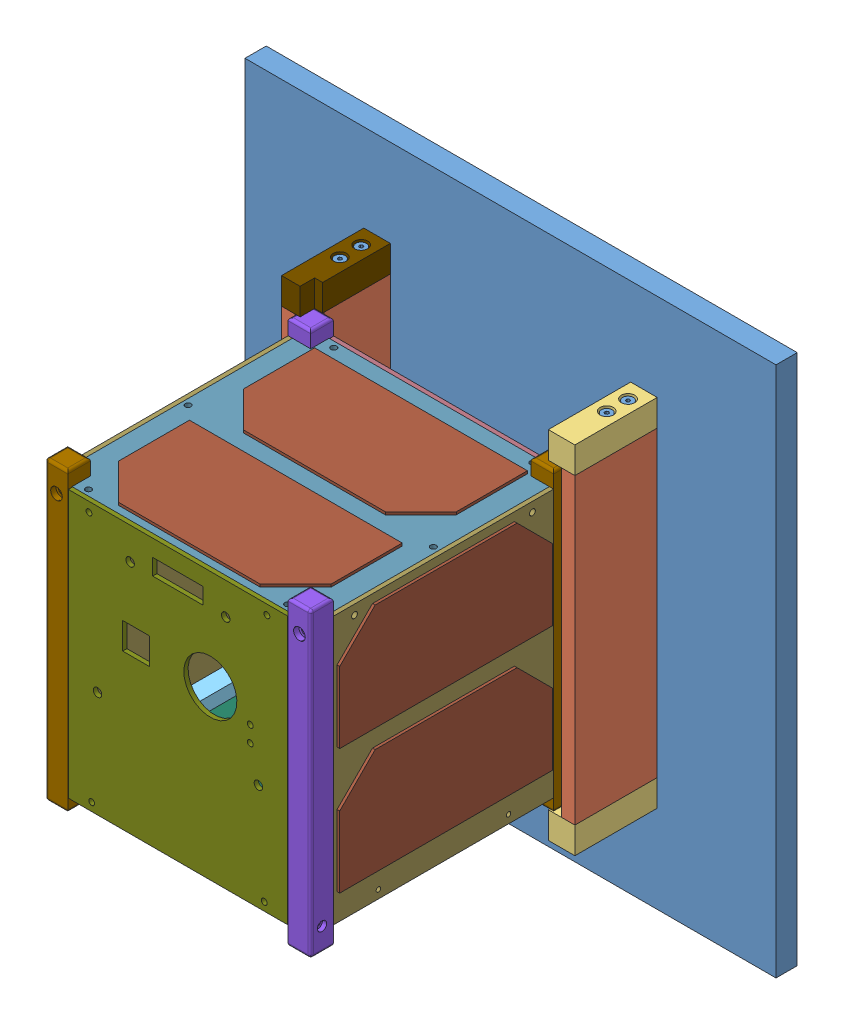
SolidWorks assembly stand_holizontal, configuration ﾃﾞﾌｫﾙﾄ. Lengths in mm.
Overall size (200 200 133).
67 component instances, 19 part files, 57 mates.
Components (placement in the parent):
- base_hori-1: base_hori [ﾃﾞﾌｫﾙﾄ] at (-92.1861 -100.1776 197.5) size (200 200 8)
- holi-1: holi [ﾃﾞﾌｫﾙﾄ] at (-47.4361 -57.1776 205.5) x (0 1 0) z (1 0 0) size (114 31 10)
- holi-3: holi [ﾃﾞﾌｫﾙﾄ] at (63.0639 56.8224 205.5) x (0 -1 0) z (-1 0 0) size (114 31 10)
- hori2-1: hori2 [ﾃﾞﾌｫﾙﾄ] at (63.0639 56.8224 205.5) x (-1 0 0) z (0 1 0) size (10 31 10)
- sample-1: sample [ﾃﾞﾌｫﾙﾄ] at (-42.4361 45.3224 330.5) x (0 0 -1) z (0 1 0) size (101 102 113.5)
  - B2_main-1: B2_main [ﾃﾞﾌｫﾙﾄ] at origin size (100 100 113.5)
    - B3_flame1-1: B3_flame1 [Default] at origin size (96.8 96.8 4)
    - B3_flame2-1: B3_flame2 [Default] at (76.5 -8.5 -87.5) x (-1 0 0) z (0 1 0) size (83 5 6.9)
    - B3_flame3-1: B3_flame3 [Default] at (100 -8.5 -85.4016) x (-1 0 0) z (0 1 0) size (6.9 5 83)
    - B3_flame4-1: B3_flame4 [Default] at (20.0069 -89.5 -26.6402) x (1 0 0) z (0 -1 0) size (6.9 16 10.5)
    - B3_flame5-1: B3_flame5 [Default] at (100 -8.5 11.5) x (-1 0 0) z (0 1 0) size (23.5 113.5 18.5)
    - B3_flame6-1: B3_flame6 [Default] at (91.5 -91.5 11.5) x (1 0 0) z (0 -1 0) size (23.5 111.5 18.5)
    - B3_flame5-2: B3_flame5 [Default] at (0 -91.5 11.5) x (1 0 0) z (0 -1 0) size (23.5 113.5 18.5)
    - B3_flame6-2: B3_flame6 [Default] at (8.5 -8.5 11.5) x (-1 0 0) z (0 1 0) size (23.5 111.5 18.5)
    - B3_flame2-2: B3_flame2 [Default] at (23.5 -91.5 -87.5) x (1 0 0) z (0 -1 0) size (83 5 6.9)
    - B3_flame3-2: B3_flame3 [Default] at (0 -91.5 -85.4016) x (1 0 0) z (0 -1 0) size (6.9 5 83)
    - B3_flame4-2: B3_flame4 [Default] at (79.9931 -10.5 -26.6402) x (-1 0 0) z (0 1 0) size (6.9 16 10.5)
    - B3_flame4-3: B3_flame4 [Default] at (-9.9069 -10.5 -26.6402) x (-1 0 0) z (0 1 0) size (6.9 16 10.5)
    - B3_flame4-4: B3_flame4 [Default] at (109.9069 -10.5 -61.3598) x (1 0 0) z (0 1 0) size (6.9 16 10.5)
    - B3_flame4-5: B3_flame4 [Default] at (109.9069 -89.5 -26.6402) x (1 0 0) z (0 -1 0) size (6.9 16 10.5)
    - B3_flame4-6: B3_flame4 [Default] at (-9.9069 -89.5 -61.3598) x (-1 0 0) z (0 -1 0) size (6.9 16 10.5)
    - B3_flame4-7: B3_flame4 [Default] at (79.9931 -89.5 -61.3598) x (-1 0 0) z (0 -1 0) size (6.9 16 10.5)
    - B3_flame4-8: B3_flame4 [Default] at (20.0069 -10.5 -61.3598) x (1 0 0) z (0 1 0) size (6.9 16 10.5)
    - B3_flame7-1: B3_flame7 [Default] at (4.25 -91.5 -96.25) x (1 0 0) z (0 -1 0) size (5.5 8.5 5)
    - B3_flame7-2: B3_flame7 [Default] at (95.75 -8.5 -96.25) x (-1 0 0) z (0 1 0) size (5.5 8.5 5)
  - B3_±Y_panel-1: B3_±Y_panel [Default] at (-6.4374 35.5175 36.7952) x (-1 0 0) z (0 0 -1) size (83 2.6 100.7)
    - Solar panel-1: Solar panel [Default] at (-43.4703 -35.5175 64.7205) size (80.15 1 40.15)
    - Solar panel-2: Solar panel [Default] at (-69.4046 -34.5175 111.8705) x (-1 0 0) z (0 0 1) size (80.15 1 40.15)
    - B2_±X_panel-2: B2_±X_panel [Default] at (-32.6974 -37.1175 99.3327) x (-1 0 0) z (0 0 -1) size (83 1.6 100.7)
  - B3_±Y_panel-2: B3_±Y_panel [Default] at (106.4374 -135.5175 36.7952) x (1 0 0) z (0 0 -1) size (83 2.6 100.7)
    - Solar panel-1: Solar panel [Default] at (-43.4703 -35.5175 64.7205) size (80.15 1 40.15)
    - Solar panel-2: Solar panel [Default] at (-69.4046 -34.5175 111.8705) x (-1 0 0) z (0 0 1) size (80.15 1 40.15)
    - B2_±X_panel-2: B2_±X_panel [Default] at (-32.6974 -37.1175 99.3327) x (-1 0 0) z (0 0 -1) size (83 1.6 100.7)
  - B3_+X_panel-1: B3_+X_panel [Default] at (78.7507 -74.7061 -48) x (0 1 0) z (0 0 -1) size (82.6 2.6 100.7)
    - Solar panel-2: Solar panel [Default] at (37.4682 21.2493 -21.6831) size (80.15 1 40.15)
    - Solar panel-3: Solar panel [Default] at (11.5339 21.2493 15.1831) x (-1 0 0) z (0 0 -1) size (80.15 1 40.15)
    - B3_+X_panel-1: B3_+X_panel [Default] at (0.9661 19.6493 -22.1375) size (82.6 1.6 100.7)
  - B3_+Z_panel-1: B3_+Z_panel [Default] at (-143.4944 -153.976 4.9) x (-1 0 0) z (0 1 0) size (96.8 2.6 96.8)
    - B2_+Z_panel-1: B2_+Z_panel [Default] at (-207.8501 -0.9 90.2045) size (96.8 1.6 96.8)
    - Solar panel-1: Solar panel [Default] at (-225.2113 0.7 116.9431) x (0 0 1) z (-1 0 0) size (80.15 1 40.15)
    - Solar panel-2: Solar panel [Default] at (-178.0613 1.7 91.0089) x (0 0 -1) z (-1 0 0) size (80.15 1 40.15)
  - B3_-Z_panel-1: B3_-Z_panel [ﾃﾞﾌｫﾙﾄ] at (67.2 -63 -89) x (1 0 0) z (0 -1 0) size (96.8 2.6 96.8)
    - B2_-Z_panel-1: B2_-Z_panel [Default] at (-49.4929 -4.5 -25.7556) x (0 0 1) z (1 0 0) size (96.8 1.6 96.8)
    - Solar panel-1: Solar panel [Default] at (15.6169 -6.1 -0.1079) x (0 0 1) z (1 0 0) size (80.15 1 40.15)
    - Solar panel-2: Solar panel [Default] at (-31.5331 -7.1 -26.0421) x (0 0 -1) z (1 0 0) size (80.15 1 40.15)
  - B3_-X_panel-1: B3_-X_panel [Default] at (0 -73.74 -25.8625) x (0 1 0) z (0 0 -1) size (82.6 1.6 100.7)
- hori2-3: hori2 [ﾃﾞﾌｫﾙﾄ] at (53.0639 -57.1776 205.5) x (1 0 0) z (0 -1 0) size (10 31 10)
- horiDS-1: horiDS [ﾃﾞﾌｫﾙﾄ] at (-47.4361 -57.1776 205.5) x (1 0 0) z (0 -1 0) size (10 31 10)
- horiDS2-1: horiDS2 [ﾃﾞﾌｫﾙﾄ] at (-37.4361 56.8224 205.5) x (-1 0 0) z (0 1 0) size (10 31 10)
- SSHS-M2-10-1: SSHS-M2-10 [ﾃﾞﾌｫﾙﾄ] at (58.0639 21.8193 201.5) x (0 0 1) z (-0.997527 0.070285 0) size (11.1 4 4)
- SSHS-M2-10-2: SSHS-M2-10 [ﾃﾞﾌｫﾙﾄ] at (58.0639 44.8224 201.5) x (0 0 1) z (-0.997527 0.070285 0) size (11.1 4 4)
- SSHS-M2-10-3: SSHS-M2-10 [ﾃﾞﾌｫﾙﾄ] at (58.3139 -0.1776 201.5) x (0 0 1) z (-0.997527 0.070285 0) size (11.1 4 4)
- SSHS-M2-10-4: SSHS-M2-10 [ﾃﾞﾌｫﾙﾄ] at (58.0639 -22.1651 201.5) x (0 0 1) z (-0.963225 0.268695 0) size (11.1 4 4)
- SSHS-M2-10-5: SSHS-M2-10 [ﾃﾞﾌｫﾙﾄ] at (58.0639 -45.1681 201.5) x (0 0 1) z (0.306571 -0.951848 0) size (11.1 4 4)
- SSHS-M2-10-6: SSHS-M2-10 [ﾃﾞﾌｫﾙﾄ] at (-42.1861 -0.1776 201.5) x (0 0 1) z (-0.997527 0.070285 0) size (11.1 4 4)
- SSHS-M2-10-7: SSHS-M2-10 [ﾃﾞﾌｫﾙﾄ] at (-42.4361 -22.1651 201.5) x (0 0 1) z (-0.997527 0.070285 0) size (11.1 4 4)
- SSHS-M2-10-8: SSHS-M2-10 [ﾃﾞﾌｫﾙﾄ] at (-42.4361 -45.1681 201.5) x (0 0 1) z (-0.997527 0.070285 0) size (11.1 4 4)
- SSHS-M2-10-9: SSHS-M2-10 [ﾃﾞﾌｫﾙﾄ] at (-42.4361 21.8193 201.5) x (0 0 1) z (-0.997527 0.070285 0) size (11.1 4 4)
- SSHS-M2-10-10: SSHS-M2-10 [ﾃﾞﾌｫﾙﾄ] at (-42.4361 44.8224 201.5) x (0 0 1) z (-0.997527 0.070285 0) size (11.1 4 4)
- SSHS-M2-10-11: SSHS-M2-10 [ﾃﾞﾌｫﾙﾄ] at (58.0639 65.2224 219.5) x (0 -1 0) z (0.48442 0 0.874835) size (11.1 4 4)
- SSHS-M2-10-12: SSHS-M2-10 [ﾃﾞﾌｫﾙﾄ] at (58.0639 65.2224 211.5) x (0 -1 0) z (0.528772 0 0.848764) size (11.1 4 4)
- SSHS-M2-10-13: SSHS-M2-10 [ﾃﾞﾌｫﾙﾄ] at (-42.4361 65.2224 219.5) x (0 -1 0) z (0.560755 0 0.827982) size (11.1 4 4)
- SSHS-M2-10-14: SSHS-M2-10 [ﾃﾞﾌｫﾙﾄ] at (-42.4361 65.2224 211.5) x (0 -1 0) z (0.50727 0 0.861787) size (11.1 4 4)
- SSHS-M2-10-15: SSHS-M2-10 [ﾃﾞﾌｫﾙﾄ] at (58.0639 -65.5776 219.5) x (0 1 0) z (0.536886 0 0.843655) size (11.1 4 4)
- SSHS-M2-10-16: SSHS-M2-10 [ﾃﾞﾌｫﾙﾄ] at (58.0639 -65.5776 211.5) x (0 1 0) z (0.577507 0 0.816386) size (11.1 4 4)
- SSHS-M2-10-17: SSHS-M2-10 [ﾃﾞﾌｫﾙﾄ] at (-42.4361 -65.5776 219.5) x (0 1 0) z (-0.546944 0 0.837169) size (11.1 4 4)
- SSHS-M2-10-18: SSHS-M2-10 [ﾃﾞﾌｫﾙﾄ] at (-42.4361 -65.5776 211.5) x (0 1 0) z (0.580214 0 0.814464) size (11.1 4 4)
Mates (geometry in assembly coordinates):
- Coincident2: coincident anti-aligned: plane of base_hori-1 through (-92.1861 -100.1776 205.5) normal (0 0 1); plane of holi-1 through (-37.4361 -57.1776 205.5) normal (0 0 -1)
- Coincident3: coincident anti-aligned: plane of base_hori-1 through (-92.1861 -100.1776 205.5) normal (0 0 1); plane of holi-3 through (53.0639 56.8224 205.5) normal (0 0 -1)
- Coincident6: coincident aligned: plane of holi-1 through (-37.4361 56.8224 205.5) normal (0 1 0); plane of holi-3 through (53.0639 56.8224 205.5) normal (0 1 0)
- Distance1: distance = 43 mm aligned: plane of holi-3 through (53.0639 56.8224 205.5) normal (0 1 0); plane of base_hori-1 through (-92.1861 99.8224 205.5) normal (0 1 0)
- Coincident15: coincident anti-aligned: plane of holi-1 through (-42.4361 -57.1776 205.5) normal (1 0 0); plane of sample-1/B2_main-1/B3_flame5-1 through (-42.4361 56.8224 230.5) normal (-1 0 0)
- Coincident16: coincident anti-aligned: plane of holi-3 through (58.0639 -57.1776 230.5) normal (0 0 1); plane of sample-1/B2_main-1/B3_flame6-1 through (57.5639 56.8224 230.5) normal (0 0 -1)
- Distance2: distance = 145.25 mm aligned: plane of base_hori-1 through (107.8139 -100.1776 205.5) normal (1 0 0); plane of holi-1 through (-37.4361 -57.1776 205.5) normal (1 0 0)
- Distance3: distance = 145.25 mm aligned: plane of holi-3 through (53.0639 56.8224 205.5) normal (-1 0 0); plane of base_hori-1 through (-92.1861 -100.1776 205.5) normal (-1 0 0)
- Coincident19: coincident anti-aligned: plane of holi-3 through (53.0639 -57.1776 205.5) normal (0 -1 0); plane of hori2-3 through (53.0639 -57.1776 205.5) normal (0 1 0)
- Coincident20: coincident aligned: plane of holi-3 through (63.0639 56.8224 205.5) normal (1 0 0); plane of hori2-3 through (63.0639 -67.1776 205.5) normal (1 0 0)
- Coincident21: coincident aligned: plane of holi-3 through (53.0639 56.8224 236.5) normal (0 0 1); plane of hori2-3 through (53.0639 -67.1776 236.5) normal (0 0 1)
- Coincident22: coincident anti-aligned: plane of holi-1 through (-37.4361 -57.1776 205.5) normal (0 -1 0); plane of horiDS-1 through (-47.4361 -57.1776 205.5) normal (0 1 0)
- Coincident23: coincident aligned: plane of holi-1 through (-47.4361 -57.1776 205.5) normal (-1 0 0); plane of horiDS-1 through (-47.4361 -67.1776 205.5) normal (-1 0 0)
- Coincident24: coincident aligned: plane of holi-1 through (-37.4361 -57.1776 236.5) normal (0 0 1); plane of horiDS-1 through (-47.4361 -67.1776 236.5) normal (0 0 1)
- Coincident28: coincident anti-aligned: plane of holi-3 through (53.0639 56.8224 205.5) normal (0 1 0); plane of hori2-1 through (63.0639 56.8224 205.5) normal (0 -1 0)
- Coincident29: coincident aligned: plane of holi-3 through (53.0639 56.8224 236.5) normal (0 0 1); plane of hori2-1 through (63.0639 66.8224 236.5) normal (0 0 1)
- Coincident30: coincident aligned: plane of holi-3 through (63.0639 56.8224 205.5) normal (1 0 0); plane of hori2-1 through (63.0639 66.8224 205.5) normal (1 0 0)
- Coincident34: coincident anti-aligned: plane of holi-1 through (-37.4361 56.8224 205.5) normal (0 1 0); plane of horiDS2-1 through (-37.4361 56.8224 205.5) normal (0 -1 0)
- Coincident35: coincident aligned: plane of holi-1 through (-47.4361 -57.1776 205.5) normal (-1 0 0); plane of horiDS2-1 through (-47.4361 66.8224 205.5) normal (-1 0 0)
- Coincident36: coincident aligned: plane of holi-1 through (-37.4361 -57.1776 236.5) normal (0 0 1); plane of horiDS2-1 through (-37.4361 66.8224 236.5) normal (0 0 1)
- Concentric1: concentric aligned: cylinder of horiDS-1 through (-42.4361 -67.1776 219.5) axis (0 -1 0) radius 2.5; cylinder of SSHS-M2-10-17 through (-42.4361 -55.5776 219.5) axis (0 -1 0) radius 0.8
- Coincident37: coincident aligned: plane of horiDS-1 through (-41.2361 -65.5776 219.5) normal (0 -1 0); circle of SSHS-M2-10-17
- Concentric2: concentric aligned: cylinder of horiDS-1 through (-42.4361 -67.1776 211.5) axis (0 -1 0) radius 2.5; cylinder of SSHS-M2-10-18 through (-42.4361 -55.5776 211.5) axis (0 -1 0) radius 0.8
- Coincident38: coincident aligned: plane of horiDS-1 through (-41.2361 -65.5776 211.5) normal (0 -1 0); circle of SSHS-M2-10-18
- Concentric3: concentric aligned: cylinder of hori2-3 through (58.0639 -67.1776 219.5) axis (0 -1 0) radius 2.5; cylinder of SSHS-M2-10-15 through (58.0639 -55.5776 219.5) axis (0 -1 0) radius 0.8
- Coincident39: coincident aligned: plane of hori2-3 through (59.2639 -65.5776 219.5) normal (0 -1 0); circle of SSHS-M2-10-15
- Concentric4: concentric aligned: cylinder of hori2-3 through (58.0639 -67.1776 211.5) axis (0 -1 0) radius 2.5; cylinder of SSHS-M2-10-16 through (58.0639 -55.5776 211.5) axis (0 -1 0) radius 0.8
- Coincident40: coincident aligned: plane of hori2-3 through (59.2639 -65.5776 211.5) normal (0 -1 0); circle of SSHS-M2-10-16
- Concentric5: concentric aligned: cylinder of hori2-1 through (58.0639 66.8224 219.5) axis (0 1 0) radius 1.2; cylinder of SSHS-M2-10-11 through (58.0639 55.2224 219.5) axis (0 1 0) radius 0.8
- Coincident41: coincident aligned: plane of hori2-1 through (56.8639 65.2224 219.5) normal (0 1 0); circle of SSHS-M2-10-11
- Concentric6: concentric aligned: cylinder of hori2-1 through (58.0639 66.8224 211.5) axis (0 1 0) radius 1.2; cylinder of SSHS-M2-10-12 through (58.0639 55.2224 211.5) axis (0 1 0) radius 0.8
- Coincident42: coincident aligned: plane of hori2-1 through (56.8639 65.2224 211.5) normal (0 1 0); circle of SSHS-M2-10-12
- Concentric7: concentric aligned: cylinder of horiDS2-1 through (-42.4361 66.8224 219.5) axis (0 1 0) radius 1.2; cylinder of SSHS-M2-10-13 through (-42.4361 55.2224 219.5) axis (0 1 0) radius 0.8
- Coincident43: coincident aligned: plane of horiDS2-1 through (-43.6361 65.2224 219.5) normal (0 1 0); circle of SSHS-M2-10-13
- Concentric8: concentric aligned: cylinder of horiDS2-1 through (-42.4361 66.8224 211.5) axis (0 1 0) radius 1.2; cylinder of SSHS-M2-10-14 through (-42.4361 55.2224 211.5) axis (0 1 0) radius 0.8
- Coincident44: coincident aligned: plane of horiDS2-1 through (-43.6361 65.2224 211.5) normal (0 1 0); circle of SSHS-M2-10-14
- Coincident45: coincident aligned: plane of SSHS-M2-10-9 through (-42.2956 23.8144 201.5) normal (0 0 1); plane of SSHS-M2-10-10 through (-42.2956 46.8175 201.5) normal (0 0 1)
- Coincident46: coincident aligned: plane of SSHS-M2-10-8 through (-42.2956 -43.173 201.5) normal (0 0 1); plane of SSHS-M2-10-9 through (-42.2956 23.8144 201.5) normal (0 0 1)
- Coincident47: coincident aligned: plane of SSHS-M2-10-7 through (-42.2956 -20.17 201.5) normal (0 0 1); plane of SSHS-M2-10-8 through (-42.2956 -43.173 201.5) normal (0 0 1)
- Coincident48: coincident aligned: plane of SSHS-M2-10-6 through (-42.0456 1.8175 201.5) normal (0 0 1); plane of SSHS-M2-10-7 through (-42.2956 -20.17 201.5) normal (0 0 1)
- Coincident49: coincident aligned: plane of SSHS-M2-10-5 through (56.1602 -45.7812 201.5) normal (0 0 1); plane of SSHS-M2-10-6 through (-42.0456 1.8175 201.5) normal (0 0 1)
- Coincident50: coincident aligned: plane of SSHS-M2-10-4 through (58.6013 -20.2386 201.5) normal (0 0 1); plane of SSHS-M2-10-5 through (56.1602 -45.7812 201.5) normal (0 0 1)
- Coincident51: coincident aligned: plane of SSHS-M2-10-3 through (58.4544 1.8175 201.5) normal (0 0 1); plane of SSHS-M2-10-4 through (58.6013 -20.2386 201.5) normal (0 0 1)
- Coincident52: coincident aligned: plane of SSHS-M2-10-2 through (58.2044 46.8175 201.5) normal (0 0 1); plane of SSHS-M2-10-3 through (58.4544 1.8175 201.5) normal (0 0 1)
- Coincident53: coincident aligned: plane of SSHS-M2-10-1 through (58.2044 23.8144 201.5) normal (0 0 1); plane of SSHS-M2-10-2 through (58.2044 46.8175 201.5) normal (0 0 1)
- Concentric9: concentric aligned: circle of base_hori-1; cylinder of SSHS-M2-10-2 through (58.0639 44.8224 211.5) axis (0 0 -1) radius 0.8
- Concentric10: concentric aligned: circle of base_hori-1; cylinder of SSHS-M2-10-1 through (58.0639 21.8193 211.5) axis (0 0 -1) radius 0.8
- Concentric11: concentric aligned: circle of base_hori-1; cylinder of SSHS-M2-10-3 through (58.3139 -0.1776 211.5) axis (0 0 -1) radius 0.8
- Concentric12: concentric aligned: circle of base_hori-1; cylinder of SSHS-M2-10-4 through (58.0639 -22.1651 211.5) axis (0 0 -1) radius 0.8
- Concentric13: concentric aligned: circle of base_hori-1; cylinder of SSHS-M2-10-5 through (58.0639 -45.1681 211.5) axis (0 0 -1) radius 0.8
- Concentric14: concentric aligned: circle of base_hori-1; cylinder of SSHS-M2-10-10 through (-42.4361 44.8224 211.5) axis (0 0 -1) radius 0.8
- Concentric15: concentric aligned: circle of base_hori-1; cylinder of SSHS-M2-10-9 through (-42.4361 21.8193 211.5) axis (0 0 -1) radius 0.8
- Concentric16: concentric aligned: circle of base_hori-1; cylinder of SSHS-M2-10-6 through (-42.1861 -0.1776 211.5) axis (0 0 -1) radius 0.8
- Concentric17: concentric aligned: circle of base_hori-1; cylinder of SSHS-M2-10-7 through (-42.4361 -22.1651 211.5) axis (0 0 -1) radius 0.8
- Concentric18: concentric aligned: circle of base_hori-1; cylinder of SSHS-M2-10-8 through (-42.4361 -45.1681 211.5) axis (0 0 -1) radius 0.8
- Coincident54: coincident aligned: plane of base_hori-1 through (-40.9361 -45.1681 201.5) normal (0 0 -1); circle of SSHS-M2-10-8
- Coincident55: coincident anti-aligned: plane of sample-1/B2_main-1/B3_flame5-1 through (-42.4361 56.8224 230.5) normal (0 1 0); plane of horiDS2-1 through (-37.4361 56.8224 205.5) normal (0 -1 0)
